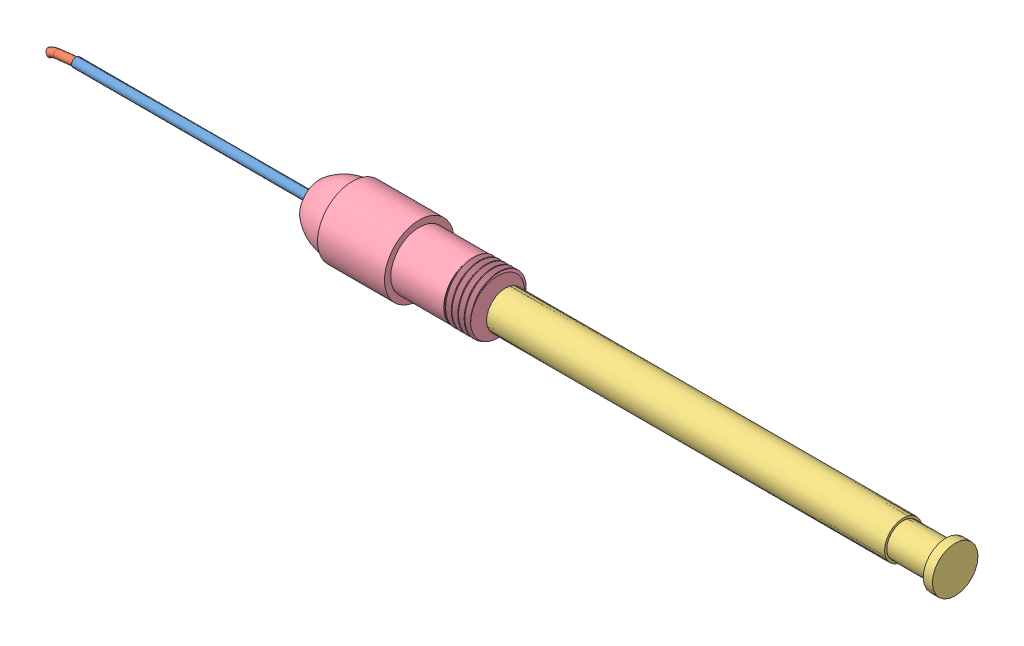
SolidWorks assembly ear drum tool, configuration Default. Lengths in mm.
Overall size (148.73 16.15 16.15).
4 component instances, 4 part files, 5 mates.
Components (placement in the parent):
- stainless steel tube 5560K43-1: stainless steel tube 5560K43 [Default] at (-6.7128 21.0808 31.4305) size (40 1.47 1.47)
- ear drum tool tip 1.16mm-1: ear drum tool tip 1.16mm [Default] at (-11.322 21.2909 31.31) x (-0.853322 -0.452327 0.259311) z (0.521384 -0.740299 0.4244) size (4.13 1.24 2.75)
- Panetti body_modified-2: Panetti body_modified [Default] at (81.6225 45.9429 31.9835) x (0 -0.999753 -0.022238) z (1 0 0) size (7.5 7.5 83.84)
- Collet amazon 0.5-3mm-1: Collet amazon 0.5-3mm [Default] at (62.8372 21.0808 31.4305) x (0 0.669765 0.742573) z (0 -0.742573 0.669765) size (11.44 29.98 11.44)
Mates (geometry in assembly coordinates):
- Coincident2: coincident anti-aligned: plane of stainless steel tube 5560K43-1 through (-6.7128 21.0808 31.4305) normal (-1 0 0); plane of ear drum tool tip 1.16mm-1 through (-6.7128 21.0808 31.4305) normal (1 0 0)
- Concentric1: concentric anti-aligned: circle of stainless steel tube 5560K43-1; circle of ear drum tool tip 1.16mm-1
- Concentric2: concentric aligned: circle of stainless steel tube 5560K43-1; circle of Collet amazon 0.5-3mm-1
- Coincident3: coincident anti-aligned: plane of stainless steel tube 5560K43-1 through (33.2872 21.0808 31.4305) normal (1 0 0); plane of Collet amazon 0.5-3mm-1 through (33.2872 21.0808 31.4305) normal (-1 0 0)
- Concentric4: concentric: circle of Panetti body_modified-2; circle of Collet amazon 0.5-3mm-1
